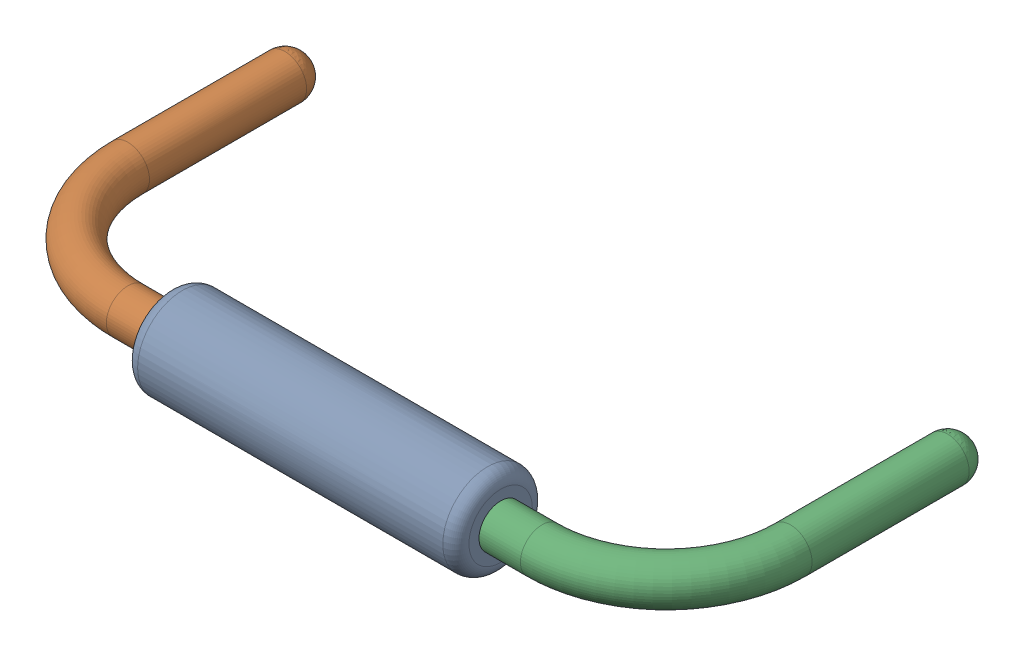
SolidWorks assembly R5, configuration Défaut. Lengths in mm.
Overall size (10.82 1.37 5.33).
4 component instances, 3 part files, 0 mates.
Components (placement in the parent):
- Open CASCADE STEP translator 6.8 1.10.1-1: Open CASCADE STEP translator 6.8 1.10.1 [Défaut] at origin size (10.82 1.37 5.33)
  - Body_1_7-1: Body_1_7 [Défaut] at origin size (5.08 1.37 1.37)
  - Pin_1_4-1: Pin_1_4 [Défaut] at origin size (3.2 0.66 4.98)
  - Pin_2_4-1: Pin_2_4 [Défaut] at (20.32 0 0) x (-1 0 0) z (0 0 1) size (3.2 0.66 4.98)
